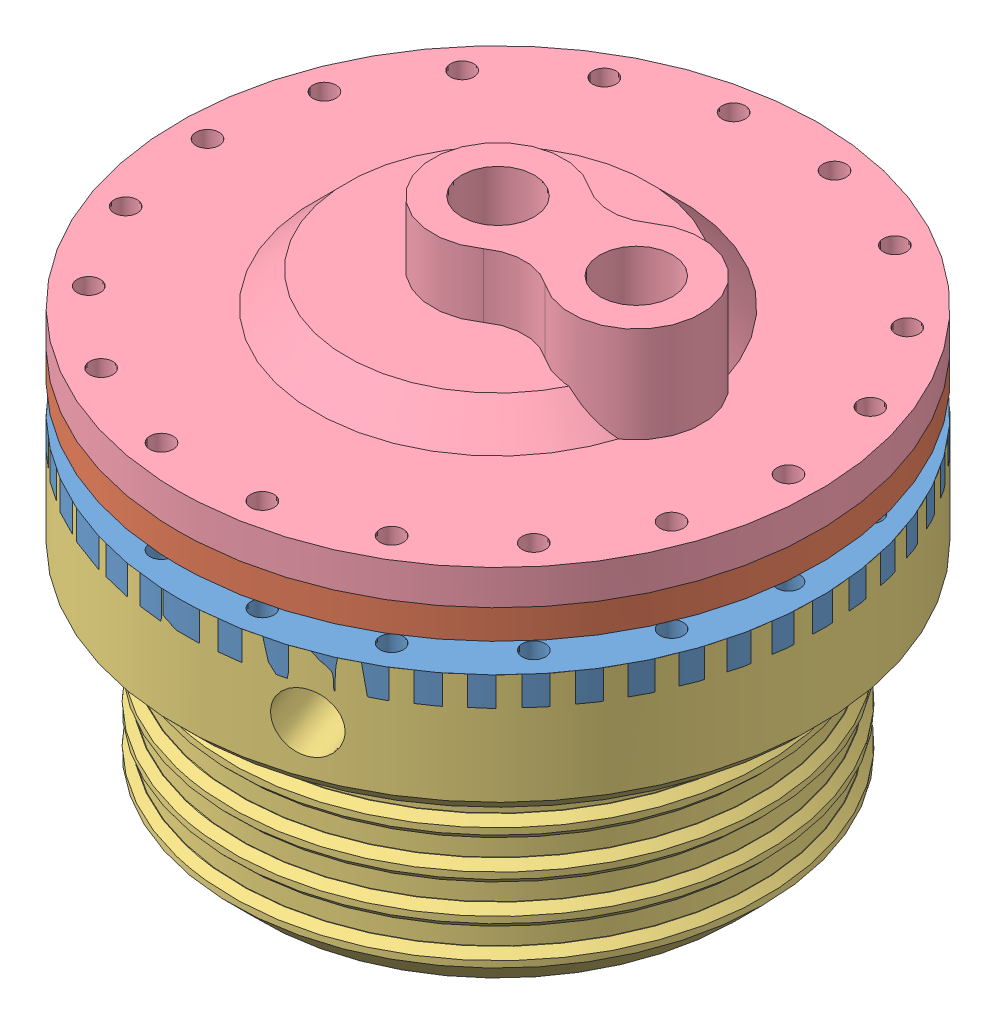
SolidWorks assembly Injector Assembly V3, configuration Default. Lengths in mm.
Overall size (161.84 111.5 161.84).
4 component instances, 4 part files, 15 mates.
Components (placement in the parent):
- Injector V3-1: Injector V3 [Default] at origin size (139.7 6.35 139.7)
- Mid Plate-1: Mid Plate [Default] at (0 6.35 0) size (139.7 15.88 139.7)
- FlangeV3-1: FlangeV3 [Default] at (0 -65.405 0) x (0.984808 0 0.173648) z (-0.173648 0 0.984808) size (139.7 70.22 139.7)
- Top Plate V3-1: Top Plate V3 [Default] at (0 12.7 0) size (139.7 28.57 139.7)
Mates (geometry in assembly coordinates):
- Concentric1: concentric aligned: cylinder of Injector V3-1 through (0 6.35 0) axis (0 -1 0) radius 69.85; cylinder of Mid Plate-1 through (0 12.7 0) axis (0 -1 0) radius 69.85
- Coincident1: coincident: plane of Injector V3-1 through (0 6.35 0) normal (0 1 0); plane of Mid Plate-1 through (0 6.35 0) normal (0 -1 0)
- Coincident2: coincident: plane of Injector V3-1 through (0 0 0) normal (0 -1 0); plane of FlangeV3-1 through (0 0 0) normal (0 1 0)
- Concentric2: concentric aligned: cylinder of Injector V3-1 through (0 6.35 0) axis (0 -1 0) radius 69.85; cylinder of FlangeV3-1 through (0 -6.35 0) axis (0 -1 0) radius 69.85
- Coincident3: coincident aligned: plane of Mid Plate-1 through (0 6.35 0) normal (0 0 1)
- Concentric4: concentric aligned: cylinder of FlangeV3-1 through (0 -6.35 0) axis (0 -1 0) radius 69.85; cylinder of Top Plate V3-1 through (0 41.275 0) axis (0 -1 0) radius 69.85
- Coincident4: coincident anti-aligned: plane of Mid Plate-1 through (0 12.7 0) normal (0 1 0); plane of Top Plate V3-1 through (0 12.7 0) normal (0 -1 0)
- Concentric5: concentric anti-aligned: cylinder of FlangeV3-1 through (0 -6.35 0) axis (0 -1 0) radius 69.85; cylinder of High Temp Epoxy-1 through (0 -214.884 0) axis (0 1 0) radius 50.8
- Coincident5: coincident anti-aligned: plane of Injector V3-1 through (0 -6.35 0) normal (0 -1 0); plane of High Temp Epoxy-1 through (0 -6.35 0) normal (0 1 0)
- Concentric6: concentric aligned: cylinder of Top Plate V3-1 through (0 12.7 0) axis (0 1 0) radius 7.9375; cylinder of -8 Swage to ORB-1 through (0 72.009 0) axis (0 1 0) radius 6.35
- Coincident6: coincident anti-aligned: plane of Top Plate V3-1 through (0 41.275 0) normal (0 1 0); plane of -8 Swage to ORB-1 through (-0.9624 41.275 -12.7955) normal (0 -1 0)
- Concentric7: concentric aligned: cylinder of Top Plate V3-1 through (30.226 12.699 0) axis (0 1 0) radius 7.9375; cylinder of -10 Swage to ORB-1 through (38.0129 73.787 2.5752) axis (0 1 0) radius 7.9375
- Coincident7: coincident anti-aligned: plane of Top Plate V3-1 through (0 41.275 0) normal (0 1 0); plane of -10 Swage to ORB-1 through (38.0129 41.275 -12.0895) normal (0 -1 0)
- Concentric8: concentric aligned: cylinder of Injector V3-1 through (-63.5 -6.35 0) axis (0 1 0) radius 2.54; cylinder of FlangeV3-1 through (-63.5 -20.955 0) axis (0 1 0) radius 2.7432
- Concentric9: concentric aligned: cylinder of Injector V3-1 through (-63.5 -6.35 0) axis (0 1 0) radius 2.54; cylinder of Top Plate V3-1 through (-63.5 12.7 0) axis (0 1 0) radius 2.54
